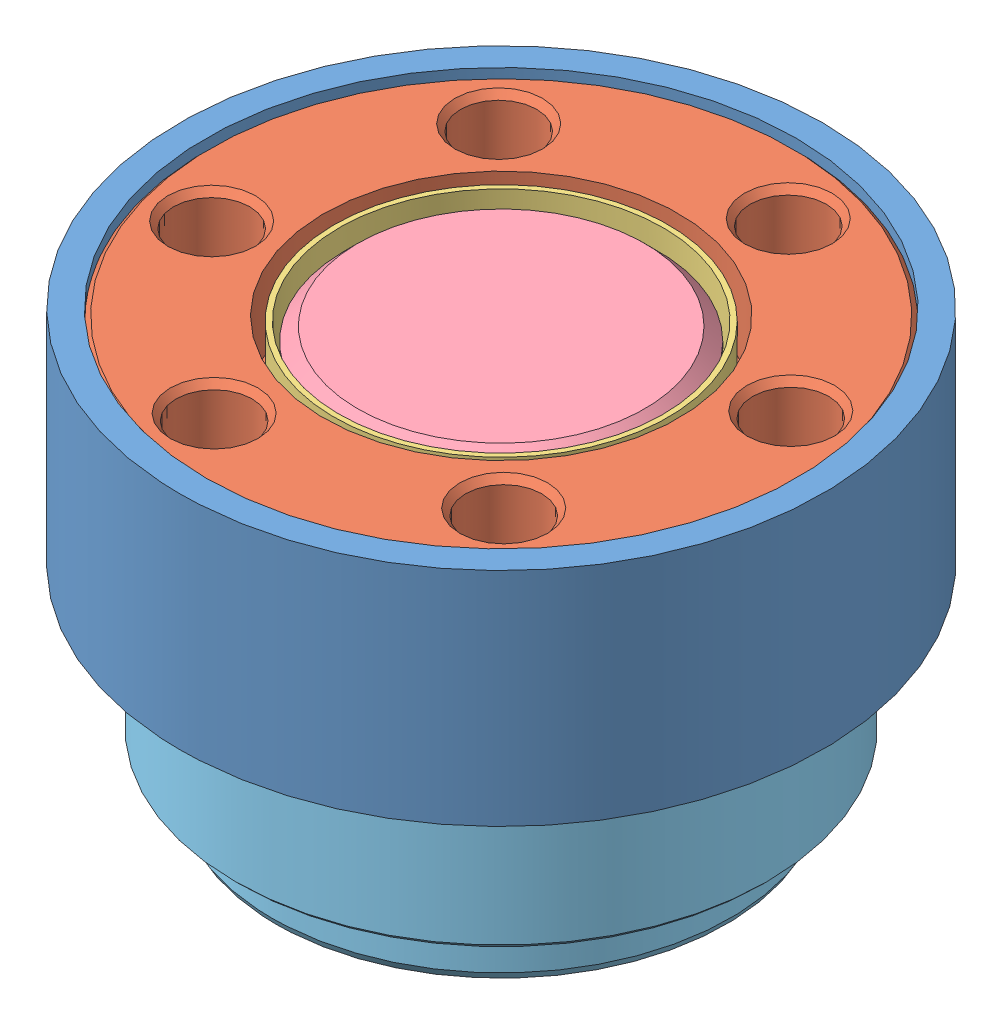
SolidWorks assembly HolderAssembly, configuration Default. Lengths in mm.
Overall size (41.19 24.13 41.19).
7 component instances, 5 part files, 4 mates.
Components (placement in the parent):
- Holder-1: Holder [Default] at (13.1291 13.671 28.0523) size (36.83 12.7 36.83)
- 1.33 Viewport-1: 1.33 Viewport [Default] at (13.1291 18.751 28.0523) x (0 1 0) z (-0.25152 0 0.967852) size (7.24 33.78 33.78)
  - 0784301N-1: 0784301N [Default] at origin size (7.24 33.78 33.78)
    - 0784101L-1: 0784101L [Default] at origin size (7.24 33.78 33.78)
    - 0194307B-1: 0194307B [Default] at (7.62 0 0) x (0 1 0) z (0 0 1) size (19.13 5.33 19.13)
  - 1002201A-1: 1002201A [Default] at (4.191 0 0) x (0 0 -1) z (1 0 0) size (17.96 17.96 2.54)
- LensTube-1: LensTube [Default] at (13.1291 13.671 28.0523) x (0 1 0) z (0 0 1) size (11.43 30.48 30.48)
Mates (geometry in assembly coordinates):
- Concentric1: concentric: cylinder of Holder-1 through (13.1291 18.751 28.0523) axis (0 1 0) radius 16.891; cylinder of 1.33 Viewport-1/0784301N-1/0784101L-1 through (13.1291 72.9166 28.0523) axis (0 -1 0) radius 16.891
- Coincident1: coincident anti-aligned: plane of Holder-1 through (13.1291 18.751 28.0523) normal (0 1 0); plane of 1.33 Viewport-1/0784301N-1/0784101L-1 through (13.1291 18.751 28.0523) normal (0 -1 0)
- Coincident2: coincident: plane of Holder-1 through (13.1291 13.671 28.0523) normal (0 -1 0); plane of LensTube-1 through (-2.1109 13.671 28.0523) normal (0 1 0)
- Concentric2: concentric anti-aligned: circle of Holder-1; circle of LensTube-1
